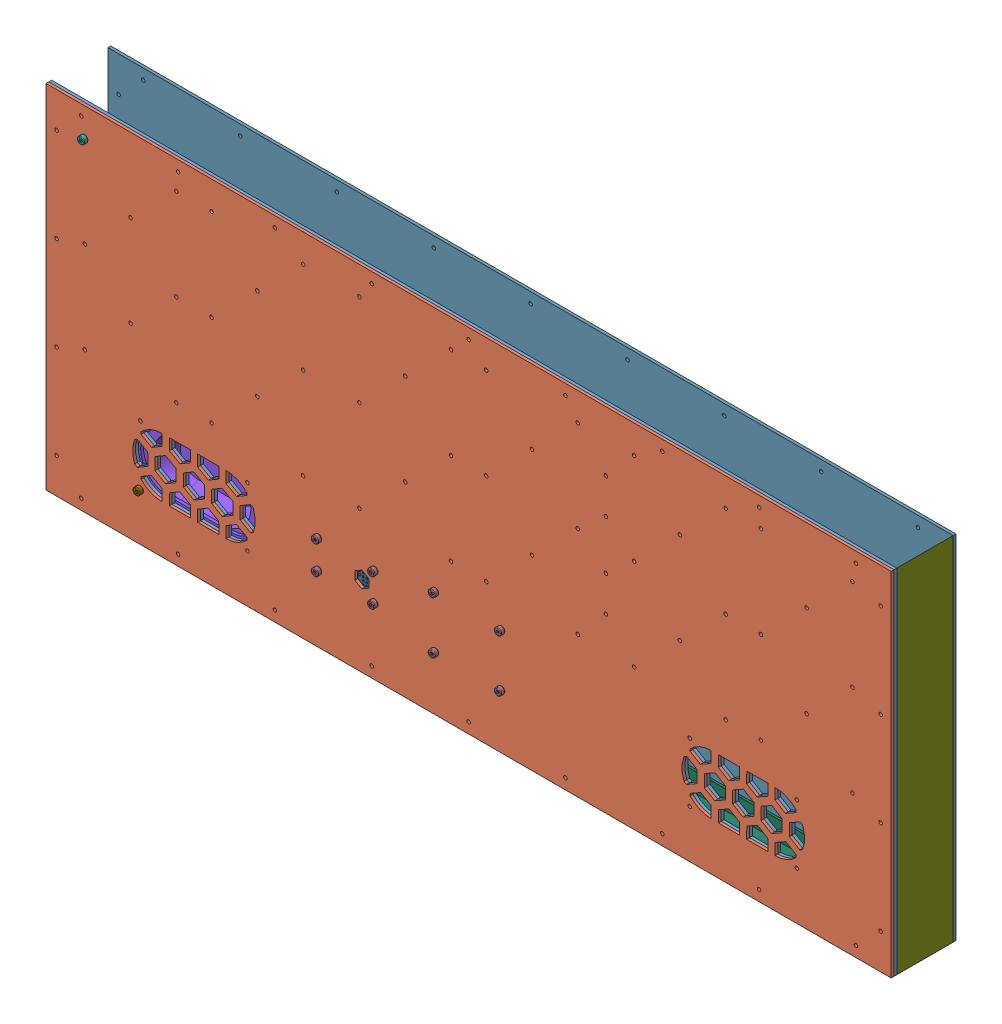
SolidWorks assembly Ensamblaje, configuration Predeterminado. Lengths in mm.
Overall size (600 250 31.87).
336 component instances, 16 part files, 54 mates.
Components (placement in the parent):
- Acrilico Frontal_back-1: Acrilico Frontal_back [Predeterminado] at (-375.8286 167.6436 436.4657) size (600 250 2)
- Acrilico Frontal_front-1: Acrilico Frontal_front [Predeterminado] at (-375.8286 167.6436 436.4657) size (600 250 2)
- Display-1: Display [Predeterminado] at (-610.5095 208.1102 290.9557) size (85 140 23) (hidden)
  - Display-1: Display [Predeterminado] at (-5.3191 -0.4666 134.5) size (85 140 11)
  - Ajuste Display-1: Ajuste Display [Predeterminado] at (-37.0959 64.7634 119.0956) size (6 6 23)
    - Separador-1: Separador [Predeterminado] at (-0.7232 -0.23 17.4044) size (6 6 9)
    - Tuerca M3-1: Tuerca M3 [Predeterminado] at (-0.7232 -0.23 13.4044) x (1 0 0) z (0 -1 0) size (5.77 2 5)
    - Tornillo M3x20_CC-1: Tornillo M3x20_CC [Predeterminado] at (-0.7232 -0.23 10.4144) size (5 5 23) (hidden)
  - Ajuste Display-2: Ajuste Display [Predeterminado] at (-4.5959 32.2634 119.0956) size (6 6 23)
    - Separador-1: Separador [Predeterminado] at (-0.7232 -0.23 17.4044) size (6 6 9)
    - Tuerca M3-1: Tuerca M3 [Predeterminado] at (-0.7232 -0.23 13.4044) x (1 0 0) z (0 -1 0) size (5.77 2 5)
    - Tornillo M3x20_CC-1: Tornillo M3x20_CC [Predeterminado] at (-0.7232 -0.23 10.4144) size (5 5 23) (hidden)
  - Ajuste Display-3: Ajuste Display [Predeterminado] at (-4.5959 -32.7366 119.0956) size (6 6 23)
    - Separador-1: Separador [Predeterminado] at (-0.7232 -0.23 17.4044) size (6 6 9)
    - Tuerca M3-1: Tuerca M3 [Predeterminado] at (-0.7232 -0.23 13.4044) x (1 0 0) z (0 -1 0) size (5.77 2 5)
    - Tornillo M3x20_CC-1: Tornillo M3x20_CC [Predeterminado] at (-0.7232 -0.23 10.4144) size (5 5 23) (hidden)
  - Ajuste Display-4: Ajuste Display [Predeterminado] at (-37.0959 -0.2366 119.0956) size (6 6 23)
    - Separador-1: Separador [Predeterminado] at (-0.7232 -0.23 17.4044) size (6 6 9)
    - Tuerca M3-1: Tuerca M3 [Predeterminado] at (-0.7232 -0.23 13.4044) x (1 0 0) z (0 -1 0) size (5.77 2 5)
    - Tornillo M3x20_CC-1: Tornillo M3x20_CC [Predeterminado] at (-0.7232 -0.23 10.4144) size (5 5 23) (hidden)
  - Ajuste Display-5: Ajuste Display [Predeterminado] at (-37.0959 -65.2366 119.0956) size (6 6 23)
    - Separador-1: Separador [Predeterminado] at (-0.7232 -0.23 17.4044) size (6 6 9)
    - Tuerca M3-1: Tuerca M3 [Predeterminado] at (-0.7232 -0.23 13.4044) x (1 0 0) z (0 -1 0) size (5.77 2 5)
    - Tornillo M3x20_CC-1: Tornillo M3x20_CC [Predeterminado] at (-0.7232 -0.23 10.4144) size (5 5 23) (hidden)
  - Ajuste Display-6: Ajuste Display [Predeterminado] at (27.9041 64.7634 119.0956) size (6 6 23)
    - Separador-1: Separador [Predeterminado] at (-0.7232 -0.23 17.4044) size (6 6 9)
    - Tuerca M3-1: Tuerca M3 [Predeterminado] at (-0.7232 -0.23 13.4044) x (1 0 0) z (0 -1 0) size (5.77 2 5)
    - Tornillo M3x20_CC-1: Tornillo M3x20_CC [Predeterminado] at (-0.7232 -0.23 10.4144) size (5 5 23) (hidden)
  - Ajuste Display-7: Ajuste Display [Predeterminado] at (27.9041 -0.2366 119.0956) size (6 6 23)
    - Separador-1: Separador [Predeterminado] at (-0.7232 -0.23 17.4044) size (6 6 9)
    - Tuerca M3-1: Tuerca M3 [Predeterminado] at (-0.7232 -0.23 13.4044) x (1 0 0) z (0 -1 0) size (5.77 2 5)
    - Tornillo M3x20_CC-1: Tornillo M3x20_CC [Predeterminado] at (-0.7232 -0.23 10.4144) size (5 5 23) (hidden)
  - Ajuste Display-8: Ajuste Display [Predeterminado] at (27.9041 -65.2366 119.0956) size (6 6 23)
    - Separador-1: Separador [Predeterminado] at (-0.7232 -0.23 17.4044) size (6 6 9)
    - Tuerca M3-1: Tuerca M3 [Predeterminado] at (-0.7232 -0.23 13.4044) x (1 0 0) z (0 -1 0) size (5.77 2 5)
    - Tornillo M3x20_CC-1: Tornillo M3x20_CC [Predeterminado] at (-0.7232 -0.23 10.4144) size (5 5 23) (hidden)
- Display-2: Display [Predeterminado] at (-130.5095 208.1102 290.9557) size (85 140 23) (hidden)
  - Display-1: Display [Predeterminado] at (-5.3191 -0.4666 134.5) size (85 140 11)
  - Ajuste Display-1: Ajuste Display [Predeterminado] at (-37.0959 64.7634 119.0956) size (6 6 23)
    - Separador-1: Separador [Predeterminado] at (-0.7232 -0.23 17.4044) size (6 6 9)
    - Tuerca M3-1: Tuerca M3 [Predeterminado] at (-0.7232 -0.23 13.4044) x (1 0 0) z (0 -1 0) size (5.77 2 5)
    - Tornillo M3x20_CC-1: Tornillo M3x20_CC [Predeterminado] at (-0.7232 -0.23 10.4144) size (5 5 23) (hidden)
  - Ajuste Display-2: Ajuste Display [Predeterminado] at (-4.5959 32.2634 119.0956) size (6 6 23)
    - Separador-1: Separador [Predeterminado] at (-0.7232 -0.23 17.4044) size (6 6 9)
    - Tuerca M3-1: Tuerca M3 [Predeterminado] at (-0.7232 -0.23 13.4044) x (1 0 0) z (0 -1 0) size (5.77 2 5)
    - Tornillo M3x20_CC-1: Tornillo M3x20_CC [Predeterminado] at (-0.7232 -0.23 10.4144) size (5 5 23) (hidden)
  - Ajuste Display-3: Ajuste Display [Predeterminado] at (-4.5959 -32.7366 119.0956) size (6 6 23)
    - Separador-1: Separador [Predeterminado] at (-0.7232 -0.23 17.4044) size (6 6 9)
    - Tuerca M3-1: Tuerca M3 [Predeterminado] at (-0.7232 -0.23 13.4044) x (1 0 0) z (0 -1 0) size (5.77 2 5)
    - Tornillo M3x20_CC-1: Tornillo M3x20_CC [Predeterminado] at (-0.7232 -0.23 10.4144) size (5 5 23) (hidden)
  - Ajuste Display-4: Ajuste Display [Predeterminado] at (-37.0959 -0.2366 119.0956) size (6 6 23)
    - Separador-1: Separador [Predeterminado] at (-0.7232 -0.23 17.4044) size (6 6 9)
    - Tuerca M3-1: Tuerca M3 [Predeterminado] at (-0.7232 -0.23 13.4044) x (1 0 0) z (0 -1 0) size (5.77 2 5)
    - Tornillo M3x20_CC-1: Tornillo M3x20_CC [Predeterminado] at (-0.7232 -0.23 10.4144) size (5 5 23) (hidden)
  - Ajuste Display-5: Ajuste Display [Predeterminado] at (-37.0959 -65.2366 119.0956) size (6 6 23)
    - Separador-1: Separador [Predeterminado] at (-0.7232 -0.23 17.4044) size (6 6 9)
    - Tuerca M3-1: Tuerca M3 [Predeterminado] at (-0.7232 -0.23 13.4044) x (1 0 0) z (0 -1 0) size (5.77 2 5)
    - Tornillo M3x20_CC-1: Tornillo M3x20_CC [Predeterminado] at (-0.7232 -0.23 10.4144) size (5 5 23) (hidden)
  - Ajuste Display-6: Ajuste Display [Predeterminado] at (27.9041 64.7634 119.0956) size (6 6 23)
    - Separador-1: Separador [Predeterminado] at (-0.7232 -0.23 17.4044) size (6 6 9)
    - Tuerca M3-1: Tuerca M3 [Predeterminado] at (-0.7232 -0.23 13.4044) x (1 0 0) z (0 -1 0) size (5.77 2 5)
    - Tornillo M3x20_CC-1: Tornillo M3x20_CC [Predeterminado] at (-0.7232 -0.23 10.4144) size (5 5 23) (hidden)
  - Ajuste Display-7: Ajuste Display [Predeterminado] at (27.9041 -0.2366 119.0956) size (6 6 23)
    - Separador-1: Separador [Predeterminado] at (-0.7232 -0.23 17.4044) size (6 6 9)
    - Tuerca M3-1: Tuerca M3 [Predeterminado] at (-0.7232 -0.23 13.4044) x (1 0 0) z (0 -1 0) size (5.77 2 5)
    - Tornillo M3x20_CC-1: Tornillo M3x20_CC [Predeterminado] at (-0.7232 -0.23 10.4144) size (5 5 23) (hidden)
  - Ajuste Display-8: Ajuste Display [Predeterminado] at (27.9041 -65.2366 119.0956) size (6 6 23)
    - Separador-1: Separador [Predeterminado] at (-0.7232 -0.23 17.4044) size (6 6 9)
    - Tuerca M3-1: Tuerca M3 [Predeterminado] at (-0.7232 -0.23 13.4044) x (1 0 0) z (0 -1 0) size (5.77 2 5)
    - Tornillo M3x20_CC-1: Tornillo M3x20_CC [Predeterminado] at (-0.7232 -0.23 10.4144) size (5 5 23) (hidden)
- Display-3: Display [Predeterminado] at (-220.5095 208.1102 290.9557) size (85 140 23) (hidden)
  - Display-1: Display [Predeterminado] at (-5.3191 -0.4666 134.5) size (85 140 11)
  - Ajuste Display-1: Ajuste Display [Predeterminado] at (-37.0959 64.7634 119.0956) size (6 6 23)
    - Separador-1: Separador [Predeterminado] at (-0.7232 -0.23 17.4044) size (6 6 9)
    - Tuerca M3-1: Tuerca M3 [Predeterminado] at (-0.7232 -0.23 13.4044) x (1 0 0) z (0 -1 0) size (5.77 2 5)
    - Tornillo M3x20_CC-1: Tornillo M3x20_CC [Predeterminado] at (-0.7232 -0.23 10.4144) size (5 5 23) (hidden)
  - Ajuste Display-2: Ajuste Display [Predeterminado] at (-4.5959 32.2634 119.0956) size (6 6 23)
    - Separador-1: Separador [Predeterminado] at (-0.7232 -0.23 17.4044) size (6 6 9)
    - Tuerca M3-1: Tuerca M3 [Predeterminado] at (-0.7232 -0.23 13.4044) x (1 0 0) z (0 -1 0) size (5.77 2 5)
    - Tornillo M3x20_CC-1: Tornillo M3x20_CC [Predeterminado] at (-0.7232 -0.23 10.4144) size (5 5 23) (hidden)
  - Ajuste Display-3: Ajuste Display [Predeterminado] at (-4.5959 -32.7366 119.0956) size (6 6 23)
    - Separador-1: Separador [Predeterminado] at (-0.7232 -0.23 17.4044) size (6 6 9)
    - Tuerca M3-1: Tuerca M3 [Predeterminado] at (-0.7232 -0.23 13.4044) x (1 0 0) z (0 -1 0) size (5.77 2 5)
    - Tornillo M3x20_CC-1: Tornillo M3x20_CC [Predeterminado] at (-0.7232 -0.23 10.4144) size (5 5 23) (hidden)
  - Ajuste Display-4: Ajuste Display [Predeterminado] at (-37.0959 -0.2366 119.0956) size (6 6 23)
    - Separador-1: Separador [Predeterminado] at (-0.7232 -0.23 17.4044) size (6 6 9)
    - Tuerca M3-1: Tuerca M3 [Predeterminado] at (-0.7232 -0.23 13.4044) x (1 0 0) z (0 -1 0) size (5.77 2 5)
    - Tornillo M3x20_CC-1: Tornillo M3x20_CC [Predeterminado] at (-0.7232 -0.23 10.4144) size (5 5 23) (hidden)
  - Ajuste Display-5: Ajuste Display [Predeterminado] at (-37.0959 -65.2366 119.0956) size (6 6 23)
    - Separador-1: Separador [Predeterminado] at (-0.7232 -0.23 17.4044) size (6 6 9)
    - Tuerca M3-1: Tuerca M3 [Predeterminado] at (-0.7232 -0.23 13.4044) x (1 0 0) z (0 -1 0) size (5.77 2 5)
    - Tornillo M3x20_CC-1: Tornillo M3x20_CC [Predeterminado] at (-0.7232 -0.23 10.4144) size (5 5 23) (hidden)
  - Ajuste Display-6: Ajuste Display [Predeterminado] at (27.9041 64.7634 119.0956) size (6 6 23)
    - Separador-1: Separador [Predeterminado] at (-0.7232 -0.23 17.4044) size (6 6 9)
    - Tuerca M3-1: Tuerca M3 [Predeterminado] at (-0.7232 -0.23 13.4044) x (1 0 0) z (0 -1 0) size (5.77 2 5)
    - Tornillo M3x20_CC-1: Tornillo M3x20_CC [Predeterminado] at (-0.7232 -0.23 10.4144) size (5 5 23) (hidden)
  - Ajuste Display-7: Ajuste Display [Predeterminado] at (27.9041 -0.2366 119.0956) size (6 6 23)
    - Separador-1: Separador [Predeterminado] at (-0.7232 -0.23 17.4044) size (6 6 9)
    - Tuerca M3-1: Tuerca M3 [Predeterminado] at (-0.7232 -0.23 13.4044) x (1 0 0) z (0 -1 0) size (5.77 2 5)
    - Tornillo M3x20_CC-1: Tornillo M3x20_CC [Predeterminado] at (-0.7232 -0.23 10.4144) size (5 5 23) (hidden)
  - Ajuste Display-8: Ajuste Display [Predeterminado] at (27.9041 -65.2366 119.0956) size (6 6 23)
    - Separador-1: Separador [Predeterminado] at (-0.7232 -0.23 17.4044) size (6 6 9)
    - Tuerca M3-1: Tuerca M3 [Predeterminado] at (-0.7232 -0.23 13.4044) x (1 0 0) z (0 -1 0) size (5.77 2 5)
    - Tornillo M3x20_CC-1: Tornillo M3x20_CC [Predeterminado] at (-0.7232 -0.23 10.4144) size (5 5 23) (hidden)
- Display-4: Display [Predeterminado] at (-325.5095 208.1102 290.9557) size (85 140 23) (hidden)
  - Display-1: Display [Predeterminado] at (-5.3191 -0.4666 134.5) size (85 140 11)
  - Ajuste Display-1: Ajuste Display [Predeterminado] at (-37.0959 64.7634 119.0956) size (6 6 23)
    - Separador-1: Separador [Predeterminado] at (-0.7232 -0.23 17.4044) size (6 6 9)
    - Tuerca M3-1: Tuerca M3 [Predeterminado] at (-0.7232 -0.23 13.4044) x (1 0 0) z (0 -1 0) size (5.77 2 5)
    - Tornillo M3x20_CC-1: Tornillo M3x20_CC [Predeterminado] at (-0.7232 -0.23 10.4144) size (5 5 23) (hidden)
  - Ajuste Display-2: Ajuste Display [Predeterminado] at (-4.5959 32.2634 119.0956) size (6 6 23)
    - Separador-1: Separador [Predeterminado] at (-0.7232 -0.23 17.4044) size (6 6 9)
    - Tuerca M3-1: Tuerca M3 [Predeterminado] at (-0.7232 -0.23 13.4044) x (1 0 0) z (0 -1 0) size (5.77 2 5)
    - Tornillo M3x20_CC-1: Tornillo M3x20_CC [Predeterminado] at (-0.7232 -0.23 10.4144) size (5 5 23) (hidden)
  - Ajuste Display-3: Ajuste Display [Predeterminado] at (-4.5959 -32.7366 119.0956) size (6 6 23)
    - Separador-1: Separador [Predeterminado] at (-0.7232 -0.23 17.4044) size (6 6 9)
    - Tuerca M3-1: Tuerca M3 [Predeterminado] at (-0.7232 -0.23 13.4044) x (1 0 0) z (0 -1 0) size (5.77 2 5)
    - Tornillo M3x20_CC-1: Tornillo M3x20_CC [Predeterminado] at (-0.7232 -0.23 10.4144) size (5 5 23) (hidden)
  - Ajuste Display-4: Ajuste Display [Predeterminado] at (-37.0959 -0.2366 119.0956) size (6 6 23)
    - Separador-1: Separador [Predeterminado] at (-0.7232 -0.23 17.4044) size (6 6 9)
    - Tuerca M3-1: Tuerca M3 [Predeterminado] at (-0.7232 -0.23 13.4044) x (1 0 0) z (0 -1 0) size (5.77 2 5)
    - Tornillo M3x20_CC-1: Tornillo M3x20_CC [Predeterminado] at (-0.7232 -0.23 10.4144) size (5 5 23) (hidden)
  - Ajuste Display-5: Ajuste Display [Predeterminado] at (-37.0959 -65.2366 119.0956) size (6 6 23)
    - Separador-1: Separador [Predeterminado] at (-0.7232 -0.23 17.4044) size (6 6 9)
    - Tuerca M3-1: Tuerca M3 [Predeterminado] at (-0.7232 -0.23 13.4044) x (1 0 0) z (0 -1 0) size (5.77 2 5)
    - Tornillo M3x20_CC-1: Tornillo M3x20_CC [Predeterminado] at (-0.7232 -0.23 10.4144) size (5 5 23) (hidden)
  - Ajuste Display-6: Ajuste Display [Predeterminado] at (27.9041 64.7634 119.0956) size (6 6 23)
    - Separador-1: Separador [Predeterminado] at (-0.7232 -0.23 17.4044) size (6 6 9)
    - Tuerca M3-1: Tuerca M3 [Predeterminado] at (-0.7232 -0.23 13.4044) x (1 0 0) z (0 -1 0) size (5.77 2 5)
    - Tornillo M3x20_CC-1: Tornillo M3x20_CC [Predeterminado] at (-0.7232 -0.23 10.4144) size (5 5 23) (hidden)
  - Ajuste Display-7: Ajuste Display [Predeterminado] at (27.9041 -0.2366 119.0956) size (6 6 23)
    - Separador-1: Separador [Predeterminado] at (-0.7232 -0.23 17.4044) size (6 6 9)
    - Tuerca M3-1: Tuerca M3 [Predeterminado] at (-0.7232 -0.23 13.4044) x (1 0 0) z (0 -1 0) size (5.77 2 5)
    - Tornillo M3x20_CC-1: Tornillo M3x20_CC [Predeterminado] at (-0.7232 -0.23 10.4144) size (5 5 23) (hidden)
  - Ajuste Display-8: Ajuste Display [Predeterminado] at (27.9041 -65.2366 119.0956) size (6 6 23)
    - Separador-1: Separador [Predeterminado] at (-0.7232 -0.23 17.4044) size (6 6 9)
    - Tuerca M3-1: Tuerca M3 [Predeterminado] at (-0.7232 -0.23 13.4044) x (1 0 0) z (0 -1 0) size (5.77 2 5)
    - Tornillo M3x20_CC-1: Tornillo M3x20_CC [Predeterminado] at (-0.7232 -0.23 10.4144) size (5 5 23) (hidden)
- Display-5: Display [Predeterminado] at (-415.5095 208.1102 290.9557) size (85 140 23) (hidden)
  - Display-1: Display [Predeterminado] at (-5.3191 -0.4666 134.5) size (85 140 11)
  - Ajuste Display-1: Ajuste Display [Predeterminado] at (-37.0959 64.7634 119.0956) size (6 6 23)
    - Separador-1: Separador [Predeterminado] at (-0.7232 -0.23 17.4044) size (6 6 9)
    - Tuerca M3-1: Tuerca M3 [Predeterminado] at (-0.7232 -0.23 13.4044) x (1 0 0) z (0 -1 0) size (5.77 2 5)
    - Tornillo M3x20_CC-1: Tornillo M3x20_CC [Predeterminado] at (-0.7232 -0.23 10.4144) size (5 5 23) (hidden)
  - Ajuste Display-2: Ajuste Display [Predeterminado] at (-4.5959 32.2634 119.0956) size (6 6 23)
    - Separador-1: Separador [Predeterminado] at (-0.7232 -0.23 17.4044) size (6 6 9)
    - Tuerca M3-1: Tuerca M3 [Predeterminado] at (-0.7232 -0.23 13.4044) x (1 0 0) z (0 -1 0) size (5.77 2 5)
    - Tornillo M3x20_CC-1: Tornillo M3x20_CC [Predeterminado] at (-0.7232 -0.23 10.4144) size (5 5 23) (hidden)
  - Ajuste Display-3: Ajuste Display [Predeterminado] at (-4.5959 -32.7366 119.0956) size (6 6 23)
    - Separador-1: Separador [Predeterminado] at (-0.7232 -0.23 17.4044) size (6 6 9)
    - Tuerca M3-1: Tuerca M3 [Predeterminado] at (-0.7232 -0.23 13.4044) x (1 0 0) z (0 -1 0) size (5.77 2 5)
    - Tornillo M3x20_CC-1: Tornillo M3x20_CC [Predeterminado] at (-0.7232 -0.23 10.4144) size (5 5 23) (hidden)
  - Ajuste Display-4: Ajuste Display [Predeterminado] at (-37.0959 -0.2366 119.0956) size (6 6 23)
    - Separador-1: Separador [Predeterminado] at (-0.7232 -0.23 17.4044) size (6 6 9)
    - Tuerca M3-1: Tuerca M3 [Predeterminado] at (-0.7232 -0.23 13.4044) x (1 0 0) z (0 -1 0) size (5.77 2 5)
    - Tornillo M3x20_CC-1: Tornillo M3x20_CC [Predeterminado] at (-0.7232 -0.23 10.4144) size (5 5 23) (hidden)
  - Ajuste Display-5: Ajuste Display [Predeterminado] at (-37.0959 -65.2366 119.0956) size (6 6 23)
    - Separador-1: Separador [Predeterminado] at (-0.7232 -0.23 17.4044) size (6 6 9)
    - Tuerca M3-1: Tuerca M3 [Predeterminado] at (-0.7232 -0.23 13.4044) x (1 0 0) z (0 -1 0) size (5.77 2 5)
    - Tornillo M3x20_CC-1: Tornillo M3x20_CC [Predeterminado] at (-0.7232 -0.23 10.4144) size (5 5 23) (hidden)
  - Ajuste Display-6: Ajuste Display [Predeterminado] at (27.9041 64.7634 119.0956) size (6 6 23)
    - Separador-1: Separador [Predeterminado] at (-0.7232 -0.23 17.4044) size (6 6 9)
    - Tuerca M3-1: Tuerca M3 [Predeterminado] at (-0.7232 -0.23 13.4044) x (1 0 0) z (0 -1 0) size (5.77 2 5)
    - Tornillo M3x20_CC-1: Tornillo M3x20_CC [Predeterminado] at (-0.7232 -0.23 10.4144) size (5 5 23) (hidden)
  - Ajuste Display-7: Ajuste Display [Predeterminado] at (27.9041 -0.2366 119.0956) size (6 6 23)
    - Separador-1: Separador [Predeterminado] at (-0.7232 -0.23 17.4044) size (6 6 9)
    - Tuerca M3-1: Tuerca M3 [Predeterminado] at (-0.7232 -0.23 13.4044) x (1 0 0) z (0 -1 0) size (5.77 2 5)
    - Tornillo M3x20_CC-1: Tornillo M3x20_CC [Predeterminado] at (-0.7232 -0.23 10.4144) size (5 5 23) (hidden)
  - Ajuste Display-8: Ajuste Display [Predeterminado] at (27.9041 -65.2366 119.0956) size (6 6 23)
    - Separador-1: Separador [Predeterminado] at (-0.7232 -0.23 17.4044) size (6 6 9)
    - Tuerca M3-1: Tuerca M3 [Predeterminado] at (-0.7232 -0.23 13.4044) x (1 0 0) z (0 -1 0) size (5.77 2 5)
    - Tornillo M3x20_CC-1: Tornillo M3x20_CC [Predeterminado] at (-0.7232 -0.23 10.4144) size (5 5 23) (hidden)
- Display-6: Display [Predeterminado] at (-520.5095 208.1102 290.9557) size (85 140 23) (hidden)
  - Display-1: Display [Predeterminado] at (-5.3191 -0.4666 134.5) size (85 140 11)
  - Ajuste Display-1: Ajuste Display [Predeterminado] at (-37.0959 64.7634 119.0956) size (6 6 23)
    - Separador-1: Separador [Predeterminado] at (-0.7232 -0.23 17.4044) size (6 6 9)
    - Tuerca M3-1: Tuerca M3 [Predeterminado] at (-0.7232 -0.23 13.4044) x (1 0 0) z (0 -1 0) size (5.77 2 5)
    - Tornillo M3x20_CC-1: Tornillo M3x20_CC [Predeterminado] at (-0.7232 -0.23 10.4144) size (5 5 23) (hidden)
  - Ajuste Display-2: Ajuste Display [Predeterminado] at (-4.5959 32.2634 119.0956) size (6 6 23)
    - Separador-1: Separador [Predeterminado] at (-0.7232 -0.23 17.4044) size (6 6 9)
    - Tuerca M3-1: Tuerca M3 [Predeterminado] at (-0.7232 -0.23 13.4044) x (1 0 0) z (0 -1 0) size (5.77 2 5)
    - Tornillo M3x20_CC-1: Tornillo M3x20_CC [Predeterminado] at (-0.7232 -0.23 10.4144) size (5 5 23) (hidden)
  - Ajuste Display-3: Ajuste Display [Predeterminado] at (-4.5959 -32.7366 119.0956) size (6 6 23)
    - Separador-1: Separador [Predeterminado] at (-0.7232 -0.23 17.4044) size (6 6 9)
    - Tuerca M3-1: Tuerca M3 [Predeterminado] at (-0.7232 -0.23 13.4044) x (1 0 0) z (0 -1 0) size (5.77 2 5)
    - Tornillo M3x20_CC-1: Tornillo M3x20_CC [Predeterminado] at (-0.7232 -0.23 10.4144) size (5 5 23) (hidden)
  - Ajuste Display-4: Ajuste Display [Predeterminado] at (-37.0959 -0.2366 119.0956) size (6 6 23)
    - Separador-1: Separador [Predeterminado] at (-0.7232 -0.23 17.4044) size (6 6 9)
    - Tuerca M3-1: Tuerca M3 [Predeterminado] at (-0.7232 -0.23 13.4044) x (1 0 0) z (0 -1 0) size (5.77 2 5)
    - Tornillo M3x20_CC-1: Tornillo M3x20_CC [Predeterminado] at (-0.7232 -0.23 10.4144) size (5 5 23) (hidden)
  - Ajuste Display-5: Ajuste Display [Predeterminado] at (-37.0959 -65.2366 119.0956) size (6 6 23)
    - Separador-1: Separador [Predeterminado] at (-0.7232 -0.23 17.4044) size (6 6 9)
    - Tuerca M3-1: Tuerca M3 [Predeterminado] at (-0.7232 -0.23 13.4044) x (1 0 0) z (0 -1 0) size (5.77 2 5)
    - Tornillo M3x20_CC-1: Tornillo M3x20_CC [Predeterminado] at (-0.7232 -0.23 10.4144) size (5 5 23) (hidden)
  - Ajuste Display-6: Ajuste Display [Predeterminado] at (27.9041 64.7634 119.0956) size (6 6 23)
    - Separador-1: Separador [Predeterminado] at (-0.7232 -0.23 17.4044) size (6 6 9)
    - Tuerca M3-1: Tuerca M3 [Predeterminado] at (-0.7232 -0.23 13.4044) x (1 0 0) z (0 -1 0) size (5.77 2 5)
    - Tornillo M3x20_CC-1: Tornillo M3x20_CC [Predeterminado] at (-0.7232 -0.23 10.4144) size (5 5 23) (hidden)
  - Ajuste Display-7: Ajuste Display [Predeterminado] at (27.9041 -0.2366 119.0956) size (6 6 23)
    - Separador-1: Separador [Predeterminado] at (-0.7232 -0.23 17.4044) size (6 6 9)
    - Tuerca M3-1: Tuerca M3 [Predeterminado] at (-0.7232 -0.23 13.4044) x (1 0 0) z (0 -1 0) size (5.77 2 5)
    - Tornillo M3x20_CC-1: Tornillo M3x20_CC [Predeterminado] at (-0.7232 -0.23 10.4144) size (5 5 23) (hidden)
  - Ajuste Display-8: Ajuste Display [Predeterminado] at (27.9041 -65.2366 119.0956) size (6 6 23)
    - Separador-1: Separador [Predeterminado] at (-0.7232 -0.23 17.4044) size (6 6 9)
    - Tuerca M3-1: Tuerca M3 [Predeterminado] at (-0.7232 -0.23 13.4044) x (1 0 0) z (0 -1 0) size (5.77 2 5)
    - Tornillo M3x20_CC-1: Tornillo M3x20_CC [Predeterminado] at (-0.7232 -0.23 10.4144) size (5 5 23) (hidden)
- Dospuntos-1: Dospuntos [Predeterminado] at (-260.2649 210.5098 330.9557) size (15 100 23) (hidden)
  - PlacaDospuntos-1: PlacaDospuntos [Predeterminado] at (-18.0638 -2.8662 96.5) size (15 100 11)
  - Ajuste Display-1: Ajuste Display [Predeterminado] at (-17.3405 39.8638 79.0956) size (6 6 23)
    - Separador-1: Separador [Predeterminado] at (-0.7232 -0.23 17.4044) size (6 6 9)
    - Tuerca M3-1: Tuerca M3 [Predeterminado] at (-0.7232 -0.23 13.4044) x (1 0 0) z (0 -1 0) size (5.77 2 5)
    - Tornillo M3x20_CC-1: Tornillo M3x20_CC [Predeterminado] at (-0.7232 -0.23 10.4144) size (5 5 23) (hidden)
  - Ajuste Display-2: Ajuste Display [Predeterminado] at (-17.3405 14.8638 79.0956) size (6 6 23)
    - Separador-1: Separador [Predeterminado] at (-0.7232 -0.23 17.4044) size (6 6 9)
    - Tuerca M3-1: Tuerca M3 [Predeterminado] at (-0.7232 -0.23 13.4044) x (1 0 0) z (0 -1 0) size (5.77 2 5)
    - Tornillo M3x20_CC-1: Tornillo M3x20_CC [Predeterminado] at (-0.7232 -0.23 10.4144) size (5 5 23) (hidden)
  - Ajuste Display-3: Ajuste Display [Predeterminado] at (-17.3405 -20.1362 79.0956) size (6 6 23)
    - Separador-1: Separador [Predeterminado] at (-0.7232 -0.23 17.4044) size (6 6 9)
    - Tuerca M3-1: Tuerca M3 [Predeterminado] at (-0.7232 -0.23 13.4044) x (1 0 0) z (0 -1 0) size (5.77 2 5)
    - Tornillo M3x20_CC-1: Tornillo M3x20_CC [Predeterminado] at (-0.7232 -0.23 10.4144) size (5 5 23) (hidden)
  - Ajuste Display-4: Ajuste Display [Predeterminado] at (-17.3405 -45.1362 79.0956) size (6 6 23)
    - Separador-1: Separador [Predeterminado] at (-0.7232 -0.23 17.4044) size (6 6 9)
    - Tuerca M3-1: Tuerca M3 [Predeterminado] at (-0.7232 -0.23 13.4044) x (1 0 0) z (0 -1 0) size (5.77 2 5)
    - Tornillo M3x20_CC-1: Tornillo M3x20_CC [Predeterminado] at (-0.7232 -0.23 10.4144) size (5 5 23) (hidden)
- Parl-1: Parl [Predeterminado] at (-575.2079 114.8609 334.9557) x (0 1 0) z (0 0 1) size (50 90 30.01) (hidden)
  - Parlante-1: Parlante [Predeterminado] at (-17.2172 -4.3793 98.5) size (50 90 23)
  - Tornillo M3x10_CC-1: Tornillo M3x10_CC [Predeterminado] at (-38.2172 33.6207 95.51) size (5 5 13)
  - Tornillo M3x10_CC-2: Tornillo M3x10_CC [Predeterminado] at (3.7828 33.6207 95.51) size (5 5 13)
  - Tornillo M3x10_CC-3: Tornillo M3x10_CC [Predeterminado] at (-38.2172 -42.3793 95.51) size (5 5 13)
  - Tornillo M3x10_CC-4: Tornillo M3x10_CC [Predeterminado] at (3.7828 -42.3793 95.51) size (5 5 13)
  - Tuerca M3-1: Tuerca M3 [Predeterminado] at (-38.2172 33.6207 96.5) x (1 0 0) z (0 -1 0) size (5.77 2 5)
  - Tuerca M3-2: Tuerca M3 [Predeterminado] at (3.7828 33.6207 96.5) x (1 0 0) z (0 -1 0) size (5.77 2 5)
  - Tuerca M3-3: Tuerca M3 [Predeterminado] at (3.7828 -42.3793 96.5) x (1 0 0) z (0 -1 0) size (5.77 2 5)
  - Tuerca M3-4: Tuerca M3 [Predeterminado] at (-38.2172 -42.3793 96.5) x (1 0 0) z (0 -1 0) size (5.77 2 5)
- Parl-2: Parl [Predeterminado] at (-185.2079 114.8609 334.9557) x (0 1 0) z (0 0 1) size (50 90 30.01) (hidden)
  - Parlante-1: Parlante [Predeterminado] at (-17.2172 -4.3793 98.5) size (50 90 23)
  - Tornillo M3x10_CC-1: Tornillo M3x10_CC [Predeterminado] at (-38.2172 33.6207 95.51) size (5 5 13)
  - Tornillo M3x10_CC-2: Tornillo M3x10_CC [Predeterminado] at (3.7828 33.6207 95.51) size (5 5 13)
  - Tornillo M3x10_CC-3: Tornillo M3x10_CC [Predeterminado] at (-38.2172 -42.3793 95.51) size (5 5 13)
  - Tornillo M3x10_CC-4: Tornillo M3x10_CC [Predeterminado] at (3.7828 -42.3793 95.51) size (5 5 13)
  - Tuerca M3-1: Tuerca M3 [Predeterminado] at (-38.2172 33.6207 96.5) x (1 0 0) z (0 -1 0) size (5.77 2 5)
  - Tuerca M3-2: Tuerca M3 [Predeterminado] at (3.7828 33.6207 96.5) x (1 0 0) z (0 -1 0) size (5.77 2 5)
  - Tuerca M3-3: Tuerca M3 [Predeterminado] at (3.7828 -42.3793 96.5) x (1 0 0) z (0 -1 0) size (5.77 2 5)
  - Tuerca M3-4: Tuerca M3 [Predeterminado] at (-38.2172 -42.3793 96.5) x (1 0 0) z (0 -1 0) size (5.77 2 5)
- dht+ir-1: dht+ir [Predeterminado] at (-470.8286 100.6436 430.8407) x (0 1 0) z (0 0 1) size (26 48 10.3)
- Mainboard-1: Mainboard [Predeterminado] at (-373.3286 100.1436 430.8407) x (0 -1 0) z (0 0 -1) size (45 55 28.62)
- Ajuste Placas-1: Ajuste Placas [Predeterminado] at (-441.912 110.1936 411.0674) size (6 6 18)
  - Separador 5mm-1: Separador 5mm [Predeterminado] at (-0.4166 -0.05 20.3883) size (6 6 5)
  - Tuerca M3-1: Tuerca M3 [Predeterminado] at (-0.4166 -0.05 16.3983) x (1 0 0) z (0 -1 0) size (5.77 2 5)
  - Tornillo M3x15_CC-1: Tornillo M3x15_CC [Predeterminado] at (-0.4166 -0.05 14.3983) size (5 5 18)
- Ajuste Placas-2: Ajuste Placas [Predeterminado] at (-481.912 90.1936 411.0674) size (6 6 18)
  - Separador 5mm-1: Separador 5mm [Predeterminado] at (-0.4166 -0.05 20.3883) size (6 6 5)
  - Tuerca M3-1: Tuerca M3 [Predeterminado] at (-0.4166 -0.05 16.3983) x (1 0 0) z (0 -1 0) size (5.77 2 5)
  - Tornillo M3x15_CC-1: Tornillo M3x15_CC [Predeterminado] at (-0.4166 -0.05 14.3983) size (5 5 18)
- Ajuste Placas-3: Ajuste Placas [Predeterminado] at (-481.912 110.1936 411.0674) size (6 6 18)
  - Separador 5mm-1: Separador 5mm [Predeterminado] at (-0.4166 -0.05 20.3883) size (6 6 5)
  - Tuerca M3-1: Tuerca M3 [Predeterminado] at (-0.4166 -0.05 16.3983) x (1 0 0) z (0 -1 0) size (5.77 2 5)
  - Tornillo M3x15_CC-1: Tornillo M3x15_CC [Predeterminado] at (-0.4166 -0.05 14.3983) size (5 5 18)
- Ajuste Placas-4: Ajuste Placas [Predeterminado] at (-441.912 90.1936 411.0674) size (6 6 18)
  - Separador 5mm-1: Separador 5mm [Predeterminado] at (-0.4166 -0.05 20.3883) size (6 6 5)
  - Tuerca M3-1: Tuerca M3 [Predeterminado] at (-0.4166 -0.05 16.3983) x (1 0 0) z (0 -1 0) size (5.77 2 5)
  - Tornillo M3x15_CC-1: Tornillo M3x15_CC [Predeterminado] at (-0.4166 -0.05 14.3983) size (5 5 18)
- Ajuste Placas-5: Ajuste Placas [Predeterminado] at (-398.912 81.6936 411.0674) size (6 6 18)
  - Separador 5mm-1: Separador 5mm [Predeterminado] at (-0.4166 -0.05 20.3883) size (6 6 5)
  - Tuerca M3-1: Tuerca M3 [Predeterminado] at (-0.4166 -0.05 16.3983) x (1 0 0) z (0 -1 0) size (5.77 2 5)
  - Tornillo M3x15_CC-1: Tornillo M3x15_CC [Predeterminado] at (-0.4166 -0.05 14.3983) size (5 5 18)
- Ajuste Placas-6: Ajuste Placas [Predeterminado] at (-351.912 118.6936 411.0674) size (6 6 18)
  - Separador 5mm-1: Separador 5mm [Predeterminado] at (-0.4166 -0.05 20.3883) size (6 6 5)
  - Tuerca M3-1: Tuerca M3 [Predeterminado] at (-0.4166 -0.05 16.3983) x (1 0 0) z (0 -1 0) size (5.77 2 5)
  - Tornillo M3x15_CC-1: Tornillo M3x15_CC [Predeterminado] at (-0.4166 -0.05 14.3983) size (5 5 18)
- Ajuste Placas-7: Ajuste Placas [Predeterminado] at (-398.912 118.6936 411.0674) size (6 6 18)
  - Separador 5mm-1: Separador 5mm [Predeterminado] at (-0.4166 -0.05 20.3883) size (6 6 5)
  - Tuerca M3-1: Tuerca M3 [Predeterminado] at (-0.4166 -0.05 16.3983) x (1 0 0) z (0 -1 0) size (5.77 2 5)
  - Tornillo M3x15_CC-1: Tornillo M3x15_CC [Predeterminado] at (-0.4166 -0.05 14.3983) size (5 5 18)
- Ajuste Placas-8: Ajuste Placas [Predeterminado] at (-351.912 81.6936 411.0674) size (6 6 18)
  - Separador 5mm-1: Separador 5mm [Predeterminado] at (-0.4166 -0.05 20.3883) size (6 6 5)
  - Tuerca M3-1: Tuerca M3 [Predeterminado] at (-0.4166 -0.05 16.3983) x (1 0 0) z (0 -1 0) size (5.77 2 5)
  - Tornillo M3x15_CC-1: Tornillo M3x15_CC [Predeterminado] at (-0.4166 -0.05 14.3983) size (5 5 18)
- Acrilico Trasero-1: Acrilico Trasero [Predeterminado] at (-375.8286 167.6436 394.4457) size (600 250 2) (hidden)
- Perfiles-1: Perfiles [Predeterminado] at (-264.7102 -96.0212 -97.1444) size (600 250 52.02) (hidden)
  - Tornillo M3x10_CC-1: Tornillo M3x10_CC [Predeterminado] at (-386.1185 381.1648 527.6101) size (5 5 13)
  - Tornillo M3x10_CC-2: Tornillo M3x10_CC [Predeterminado] at (-403.6185 363.6648 527.6101) size (5 5 13)
  - Tornillo M3x10_CC-3: Tornillo M3x10_CC [Predeterminado] at (-403.6185 363.6648 501.5901) x (1 0 0) z (0 0 -1) size (5 5 13)
  - Tornillo M3x10_CC-4: Tornillo M3x10_CC [Predeterminado] at (-386.1185 381.1648 501.5901) x (1 0 0) z (0 0 -1) size (5 5 13)
  - Tornillo M3x10_CC-5: Tornillo M3x10_CC [Predeterminado] at (-386.1185 146.1648 501.5901) x (1 0 0) z (0 0 -1) size (5 5 13)
  - Tornillo M3x10_CC-6: Tornillo M3x10_CC [Predeterminado] at (-317.3685 381.1648 501.5901) x (1 0 0) z (0 0 -1) size (5 5 13)
  - Tornillo M3x10_CC-7: Tornillo M3x10_CC [Predeterminado] at (-317.3685 146.1648 501.5901) x (1 0 0) z (0 0 -1) size (5 5 13)
  - Tornillo M3x10_CC-8: Tornillo M3x10_CC [Predeterminado] at (-248.6185 381.1648 501.5901) x (1 0 0) z (0 0 -1) size (5 5 13)
  - Tornillo M3x10_CC-9: Tornillo M3x10_CC [Predeterminado] at (-248.6185 146.1648 501.5901) x (1 0 0) z (0 0 -1) size (5 5 13)
  - Tornillo M3x10_CC-10: Tornillo M3x10_CC [Predeterminado] at (-179.8685 381.1648 501.5901) x (1 0 0) z (0 0 -1) size (5 5 13)
  - Tornillo M3x10_CC-11: Tornillo M3x10_CC [Predeterminado] at (-179.8685 146.1648 501.5901) x (1 0 0) z (0 0 -1) size (5 5 13)
  - Tornillo M3x10_CC-12: Tornillo M3x10_CC [Predeterminado] at (-111.1185 381.1648 501.5901) x (1 0 0) z (0 0 -1) size (5 5 13)
  - Tornillo M3x10_CC-13: Tornillo M3x10_CC [Predeterminado] at (-111.1185 146.1648 501.5901) x (1 0 0) z (0 0 -1) size (5 5 13)
  - Tornillo M3x10_CC-14: Tornillo M3x10_CC [Predeterminado] at (-42.3685 381.1648 501.5901) x (1 0 0) z (0 0 -1) size (5 5 13)
  - Tornillo M3x10_CC-15: Tornillo M3x10_CC [Predeterminado] at (-42.3685 146.1648 501.5901) x (1 0 0) z (0 0 -1) size (5 5 13)
  - Tornillo M3x10_CC-16: Tornillo M3x10_CC [Predeterminado] at (26.3815 381.1648 501.5901) x (1 0 0) z (0 0 -1) size (5 5 13)
  - Tornillo M3x10_CC-17: Tornillo M3x10_CC [Predeterminado] at (26.3815 146.1648 501.5901) x (1 0 0) z (0 0 -1) size (5 5 13)
  - Tornillo M3x10_CC-18: Tornillo M3x10_CC [Predeterminado] at (95.1315 381.1648 501.5901) x (1 0 0) z (0 0 -1) size (5 5 13)
  - Tornillo M3x10_CC-19: Tornillo M3x10_CC [Predeterminado] at (95.1315 146.1648 501.5901) x (1 0 0) z (0 0 -1) size (5 5 13)
  - Tornillo M3x10_CC-20: Tornillo M3x10_CC [Predeterminado] at (163.8815 381.1648 501.5901) x (1 0 0) z (0 0 -1) size (5 5 13)
  - Tornillo M3x10_CC-21: Tornillo M3x10_CC [Predeterminado] at (163.8815 146.1648 501.5901) x (1 0 0) z (0 0 -1) size (5 5 13)
  - Tornillo M3x10_CC-22: Tornillo M3x10_CC [Predeterminado] at (-386.1185 146.1648 527.6101) size (5 5 13)
  - Tornillo M3x10_CC-23: Tornillo M3x10_CC [Predeterminado] at (-317.3685 381.1648 527.6101) size (5 5 13)
  - Tornillo M3x10_CC-24: Tornillo M3x10_CC [Predeterminado] at (-317.3685 146.1648 527.6101) size (5 5 13)
  - Tornillo M3x10_CC-25: Tornillo M3x10_CC [Predeterminado] at (-248.6185 381.1648 527.6101) size (5 5 13)
  - Tornillo M3x10_CC-26: Tornillo M3x10_CC [Predeterminado] at (-248.6185 146.1648 527.6101) size (5 5 13)
  - Tornillo M3x10_CC-27: Tornillo M3x10_CC [Predeterminado] at (-179.8685 381.1648 527.6101) size (5 5 13)
  - Tornillo M3x10_CC-28: Tornillo M3x10_CC [Predeterminado] at (-179.8685 146.1648 527.6101) size (5 5 13)
  - Tornillo M3x10_CC-29: Tornillo M3x10_CC [Predeterminado] at (-111.1185 381.1648 527.6101) size (5 5 13)
  - Tornillo M3x10_CC-30: Tornillo M3x10_CC [Predeterminado] at (-111.1185 146.1648 527.6101) size (5 5 13)
  - Tornillo M3x10_CC-31: Tornillo M3x10_CC [Predeterminado] at (-42.3685 381.1648 527.6101) size (5 5 13)
  - Tornillo M3x10_CC-32: Tornillo M3x10_CC [Predeterminado] at (-42.3685 146.1648 527.6101) size (5 5 13)
  - Tornillo M3x10_CC-33: Tornillo M3x10_CC [Predeterminado] at (26.3815 381.1648 527.6101) size (5 5 13)
  - Tornillo M3x10_CC-34: Tornillo M3x10_CC [Predeterminado] at (26.3815 146.1648 527.6101) size (5 5 13)
  - Tornillo M3x10_CC-35: Tornillo M3x10_CC [Predeterminado] at (95.1315 381.1648 527.6101) size (5 5 13)
  - Tornillo M3x10_CC-36: Tornillo M3x10_CC [Predeterminado] at (95.1315 146.1648 527.6101) size (5 5 13)
  - Tornillo M3x10_CC-37: Tornillo M3x10_CC [Predeterminado] at (163.8815 381.1648 527.6101) size (5 5 13)
  - Tornillo M3x10_CC-38: Tornillo M3x10_CC [Predeterminado] at (163.8815 146.1648 527.6101) size (5 5 13)
  - Tornillo M3x10_CC-39: Tornillo M3x10_CC [Predeterminado] at (-403.6185 296.9948 501.5901) x (1 0 0) z (0 0 -1) size (5 5 13)
  - Tornillo M3x10_CC-40: Tornillo M3x10_CC [Predeterminado] at (-403.6185 230.3248 501.5901) x (1 0 0) z (0 0 -1) size (5 5 13)
  - Tornillo M3x10_CC-41: Tornillo M3x10_CC [Predeterminado] at (-403.6185 163.6548 501.5901) x (1 0 0) z (0 0 -1) size (5 5 13)
  - Tornillo M3x10_CC-42: Tornillo M3x10_CC [Predeterminado] at (181.3815 363.6648 501.5901) x (1 0 0) z (0 0 -1) size (5 5 13)
  - Tornillo M3x10_CC-43: Tornillo M3x10_CC [Predeterminado] at (181.3815 296.9948 501.5901) x (1 0 0) z (0 0 -1) size (5 5 13)
  - Tornillo M3x10_CC-44: Tornillo M3x10_CC [Predeterminado] at (181.3815 230.3248 501.5901) x (1 0 0) z (0 0 -1) size (5 5 13)
  - Tornillo M3x10_CC-45: Tornillo M3x10_CC [Predeterminado] at (181.3815 163.6548 501.5901) x (1 0 0) z (0 0 -1) size (5 5 13)
  - Tornillo M3x10_CC-46: Tornillo M3x10_CC [Predeterminado] at (-403.6185 296.9948 527.6101) size (5 5 13)
  - Tornillo M3x10_CC-47: Tornillo M3x10_CC [Predeterminado] at (-403.6185 230.3248 527.6101) size (5 5 13)
  - Tornillo M3x10_CC-48: Tornillo M3x10_CC [Predeterminado] at (-403.6185 163.6548 527.6101) size (5 5 13)
  - Tornillo M3x10_CC-49: Tornillo M3x10_CC [Predeterminado] at (181.3815 363.6648 527.6101) size (5 5 13)
  - Tornillo M3x10_CC-50: Tornillo M3x10_CC [Predeterminado] at (181.3815 296.9948 527.6101) size (5 5 13)
  - Tornillo M3x10_CC-51: Tornillo M3x10_CC [Predeterminado] at (181.3815 230.3248 527.6101) size (5 5 13)
  - Tornillo M3x10_CC-52: Tornillo M3x10_CC [Predeterminado] at (181.3815 163.6548 527.6101) size (5 5 13)
  - Perfil_Largo_alum-1: Perfil_Largo_alum [Predeterminado] at (-411.1185 138.6648 513.6001) size (600 15 40)
  - Perfil_Corto_alum-1: Perfil_Corto_alum [Predeterminado] at (188.8815 138.6648 513.6001) x (0 1 0) z (0 0 1) size (250 15 40)
  - Perfil_Corto_alum-2: Perfil_Corto_alum [Predeterminado] at (-411.1185 388.6648 513.6001) x (0 -1 0) z (0 0 1) size (250 15 40)
  - Perfil_Largo_alum-2: Perfil_Largo_alum [Predeterminado] at (188.8815 388.6648 513.6001) x (-1 0 0) z (0 0 1) size (600 15 40)
Mates (geometry in assembly coordinates):
- Concéntrica44: concentric aligned: circle of ?; circle of ?
- Distancia44: distance = 5.01 mm aligned: plane of ? through (-124.7334 -46.6836 597.49) normal (0 0 1); plane of ? through (-124.7334 -46.6836 602.5) normal (0 0 1)
- Concéntrica46: concentric aligned: circle of ?; circle of ?
- Distancia46: distance = 5.01 mm aligned: plane of ? through (-124.7334 -46.6836 597.49) normal (0 0 1); plane of ? through (-124.7334 -46.6836 602.5) normal (0 0 1)
- Concéntrica48: concentric aligned: circle of ?; circle of ?
- Distancia48: distance = 5.01 mm aligned: plane of ? through (-1335.773 215.6434 1962.6356) normal (0 0 1); plane of ? through (-1335.773 215.6434 1967.6456) normal (0 0 1)
- Concéntrica52: concentric aligned: circle of ?; circle of ?
- Distancia52: distance = 5.01 mm aligned: plane of ? through (-124.7334 -46.6836 597.49) normal (0 0 1); plane of ? through (-124.7334 -46.6836 602.5) normal (0 0 1)
- Coincidente1: coincident aligned: plane of Acrilico Frontal_back-1 through (-675.8286 42.6436 440.4657) normal (-1 0 0); plane of Acrilico Frontal_front-1 through (-675.8286 42.6436 440.4657) normal (-1 0 0)
- Coincidente2: coincident aligned: plane of Acrilico Frontal_back-1 through (-675.8286 292.6436 440.4657) normal (0 1 0); plane of Acrilico Frontal_front-1 through (-675.8286 292.6436 440.4657) normal (0 1 0)
- Coincidente3: coincident: line of Acrilico Frontal_back-1 through (-675.8286 292.6436 438.4657) axis (0 -1 0); plane of Acrilico Frontal_front-1 through (-375.8286 167.6436 438.4657) normal (0 0 -1)
- Coincidente4: coincident anti-aligned: plane of Acrilico Frontal_front-1 through (-375.8286 167.6436 440.4657) normal (0 0 1); plane of Display-1/Ajuste Display-6/Tornillo M3x20_CC-1 through (-583.3286 272.6436 440.4657) normal (0 0 -1)
- Concéntrica53: concentric aligned: cylinder of Acrilico Frontal_back-1 through (-648.3286 272.6436 438.4657) axis (0 0 -1) radius 1.25; cylinder of Display-1/Ajuste Display-1/Tornillo M3x20_CC-1 through (-648.3286 272.6436 440.4657) axis (0 0 -1) radius 1.5
- Bloquear1: lock: unknown of Acrilico Frontal_back-1; unknown of Display-1/Display-1
- Coincidente5: coincident aligned: plane of Display-2/Display-1 through (-135.8286 207.6436 425.4557) normal (0 0 -1); plane of Display-3/Display-1 through (-225.8286 207.6436 425.4557) normal (0 0 -1)
- Coincidente6: coincident aligned: plane of Display-3/Display-1 through (-225.8286 207.6436 425.4557) normal (0 0 -1); plane of Display-4/Display-1 through (-330.8286 207.6436 425.4557) normal (0 0 -1)
- Coincidente7: coincident aligned: plane of Display-4/Display-1 through (-330.8286 207.6436 425.4557) normal (0 0 -1); plane of Display-5/Display-1 through (-420.8286 207.6436 425.4557) normal (0 0 -1)
- Coincidente8: coincident aligned: plane of Display-5/Display-1 through (-420.8286 207.6436 425.4557) normal (0 0 -1); plane of Display-6/Display-1 through (-525.8286 207.6436 425.4557) normal (0 0 -1)
- Concéntrica54: concentric aligned: cylinder of Acrilico Frontal_back-1 through (-493.3286 272.6436 438.4657) axis (0 0 -1) radius 1.25; cylinder of Display-6/Ajuste Display-6/Tornillo M3x20_CC-1 through (-493.3286 272.6436 440.4657) axis (0 0 -1) radius 1.5
- Concéntrica55: concentric aligned: cylinder of Acrilico Frontal_back-1 through (-388.3286 272.6436 438.4657) axis (0 0 -1) radius 1.25; cylinder of Display-5/Ajuste Display-6/Tornillo M3x20_CC-1 through (-388.3286 272.6436 440.4657) axis (0 0 -1) radius 1.5
- Concéntrica56: concentric aligned: cylinder of Acrilico Frontal_back-1 through (-298.3286 272.6436 438.4657) axis (0 0 -1) radius 1.25; cylinder of Display-4/Ajuste Display-6/Tornillo M3x20_CC-1 through (-298.3286 272.6436 440.4657) axis (0 0 -1) radius 1.5
- Concéntrica57: concentric aligned: cylinder of Acrilico Frontal_front-1 through (-193.3286 272.6436 438.4657) axis (0 0 -1) radius 1.25; cylinder of Display-3/Ajuste Display-6/Tornillo M3x20_CC-1 through (-193.3286 272.6436 440.4657) axis (0 0 -1) radius 1.5
- Concéntrica58: concentric aligned: cylinder of Acrilico Frontal_front-1 through (-103.3286 272.6436 438.4657) axis (0 0 -1) radius 1.25; cylinder of Display-2/Ajuste Display-6/Tornillo M3x20_CC-1 through (-103.3286 272.6436 440.4657) axis (0 0 -1) radius 1.5
- Coincidente9: coincident aligned: plane of Display-1/Display-1 through (-615.8286 207.6436 425.4557) normal (0 0 -1); plane of Display-6/Display-1 through (-525.8286 207.6436 425.4557) normal (0 0 -1)
- Coincidente10: coincident aligned: plane of Display-1/Display-1 through (-615.8286 207.6436 425.4557) normal (0 0 -1); plane of Dospuntos-1/PlacaDospuntos-1 through (-278.3286 207.6436 425.4557) normal (0 0 -1)
- Concéntrica59: concentric aligned: cylinder of Acrilico Frontal_back-1 through (-278.3286 250.1436 440.4657) axis (0 0 -1) radius 1.25; cylinder of Dospuntos-1/Ajuste Display-1/Tornillo M3x20_CC-1 through (-278.3286 250.1436 440.4657) axis (0 0 -1) radius 1.5
- Coincidente11: coincident aligned: plane of Parl-1/Parlante-1 through (-529.8286 76.6436 433.4557) normal (0 0 -1); plane of Parl-2/Parlante-1 through (-139.8286 76.6436 433.4557) normal (0 0 -1)
- Coincidente12: coincident anti-aligned: plane of Acrilico Frontal_front-1 through (-375.8286 167.6436 440.4657) normal (0 0 1); plane of Parl-1/Tornillo M3x10_CC-2 through (-608.8286 118.6436 440.4657) normal (0 0 -1)
- Concéntrica60: concentric aligned: circle of Acrilico Frontal_front-1; circle of Parl-1/Tornillo M3x10_CC-2
- Concéntrica61: concentric aligned: circle of Acrilico Frontal_front-1; circle of Parl-2/Tornillo M3x10_CC-2
- Concéntrica62: concentric aligned: cylinder of Acrilico Frontal_front-1 through (-482.3286 110.1436 440.4657) axis (0 0 -1) radius 1.25; cylinder of dht+ir-1 through (-482.3286 110.1436 430.2157) axis (0 0 -1) radius 1.5
- Distancia53: distance = 5 mm anti-aligned: plane of dht+ir-1 through (-486.3286 114.1436 431.4657) normal (0 0 1); plane of Acrilico Frontal_back-1 through (-375.8286 167.6436 436.4657) normal (0 0 -1)
- Coincidente14: coincident aligned: plane of dht+ir-1 through (-486.3286 114.1436 431.4657) normal (0 0 1); plane of Mainboard-1 through (-403.3286 77.6436 431.4657) normal (0 0 1)
- Concéntrica63: concentric anti-aligned: cylinder of Acrilico Frontal_back-1 through (-352.3286 118.6436 440.4657) axis (0 0 -1) radius 1.25; cylinder of Mainboard-1 through (-352.3286 118.6436 431.4657) axis (0 0 1) radius 1.5
- Coincidente15: coincident aligned: plane of Ajuste Placas-6/Separador 5mm-1 through (-352.3286 118.6436 431.4557) normal (0 0 -1); plane of Ajuste Placas-7/Separador 5mm-1 through (-399.3286 118.6436 431.4557) normal (0 0 -1)
- Coincidente16: coincident aligned: plane of Ajuste Placas-7/Separador 5mm-1 through (-399.3286 118.6436 431.4557) normal (0 0 -1); plane of Ajuste Placas-8/Separador 5mm-1 through (-352.3286 81.6436 431.4557) normal (0 0 -1)
- Coincidente17: coincident aligned: plane of Ajuste Placas-5/Separador 5mm-1 through (-399.3286 81.6436 431.4557) normal (0 0 -1); plane of Ajuste Placas-6/Separador 5mm-1 through (-352.3286 118.6436 431.4557) normal (0 0 -1)
- Coincidente18: coincident aligned: plane of Ajuste Placas-4/Separador 5mm-1 through (-442.3286 90.1436 431.4557) normal (0 0 -1); plane of Ajuste Placas-5/Separador 5mm-1 through (-399.3286 81.6436 431.4557) normal (0 0 -1)
- Coincidente19: coincident aligned: plane of Ajuste Placas-1/Separador 5mm-1 through (-442.3286 110.1436 431.4557) normal (0 0 -1); plane of Ajuste Placas-6/Separador 5mm-1 through (-352.3286 118.6436 431.4557) normal (0 0 -1)
- Coincidente20: coincident aligned: plane of Ajuste Placas-2/Separador 5mm-1 through (-482.3286 90.1436 431.4557) normal (0 0 -1); plane of Ajuste Placas-3/Separador 5mm-1 through (-482.3286 110.1436 431.4557) normal (0 0 -1)
- Coincidente21: coincident aligned: plane of Ajuste Placas-3/Separador 5mm-1 through (-482.3286 110.1436 431.4557) normal (0 0 -1); plane of Ajuste Placas-7/Separador 5mm-1 through (-399.3286 118.6436 431.4557) normal (0 0 -1)
- Concéntrica64: concentric anti-aligned: cylinder of Mainboard-1 through (-352.3286 118.6436 431.4657) axis (0 0 1) radius 1.5; cylinder of Ajuste Placas-6/Separador 5mm-1 through (-352.3286 118.6436 436.4557) axis (0 0 -1) radius 3
- Concéntrica65: concentric anti-aligned: cylinder of Mainboard-1 through (-399.3286 118.6436 431.4657) axis (0 0 1) radius 1.5; cylinder of Ajuste Placas-7/Separador 5mm-1 through (-399.3286 118.6436 436.4557) axis (0 0 -1) radius 3
- Concéntrica66: concentric anti-aligned: cylinder of Mainboard-1 through (-352.3286 81.6436 431.4657) axis (0 0 1) radius 1.5; cylinder of Ajuste Placas-8/Separador 5mm-1 through (-352.3286 81.6436 436.4557) axis (0 0 -1) radius 3
- Concéntrica67: concentric anti-aligned: cylinder of Mainboard-1 through (-399.3286 81.6436 431.4657) axis (0 0 1) radius 1.5; cylinder of Ajuste Placas-5/Separador 5mm-1 through (-399.3286 81.6436 436.4557) axis (0 0 -1) radius 3
- Concéntrica68: concentric aligned: cylinder of Acrilico Frontal_back-1 through (-442.3286 90.1436 440.4657) axis (0 0 -1) radius 1.25; cylinder of Ajuste Placas-4/Separador 5mm-1 through (-442.3286 90.1436 436.4557) axis (0 0 -1) radius 3
- Concéntrica69: concentric aligned: cylinder of Acrilico Frontal_back-1 through (-442.3286 110.1436 440.4657) axis (0 0 -1) radius 1.25; cylinder of Ajuste Placas-1/Separador 5mm-1 through (-442.3286 110.1436 436.4557) axis (0 0 -1) radius 3
- Concéntrica70: concentric aligned: cylinder of Acrilico Frontal_back-1 through (-482.3286 110.1436 440.4657) axis (0 0 -1) radius 1.25; cylinder of Ajuste Placas-3/Separador 5mm-1 through (-482.3286 110.1436 436.4557) axis (0 0 -1) radius 3
- Concéntrica72: concentric aligned: cylinder of Acrilico Frontal_back-1 through (-482.3286 90.1436 440.4657) axis (0 0 -1) radius 1.25; cylinder of Ajuste Placas-2/Separador 5mm-1 through (-482.3286 90.1436 436.4557) axis (0 0 -1) radius 3
- Coincidente22: coincident anti-aligned: plane of Acrilico Frontal_front-1 through (-375.8286 167.6436 440.4657) normal (0 0 1); plane of Ajuste Placas-2/Tornillo M3x15_CC-1 through (-482.3286 90.1436 440.4657) normal (0 0 -1)
- Concéntrica74: concentric aligned: cylinder of Acrilico Frontal_back-1 through (-482.3286 90.1436 440.4657) axis (0 0 -1) radius 1.25; cylinder of Ajuste Placas-2/Separador 5mm-1 through (-482.3286 90.1436 436.4557) axis (0 0 -1) radius 3
- Coincidente29: coincident anti-aligned: plane of Acrilico Frontal_front-1 through (-375.8286 167.6436 440.4657) normal (0 0 1); plane of Perfiles-1/Tornillo M3x10_CC-2 through (-668.3286 267.6436 440.4657) normal (0 0 -1)
- Coincidente30: coincident aligned: plane of Acrilico Frontal_back-1 through (-675.8286 42.6436 440.4657) normal (-1 0 0); plane of Perfiles-1/Perfil_Corto_alum-2 through (-675.8286 42.6436 436.4557) normal (-1 0 0)
- Coincidente31: coincident aligned: plane of Acrilico Frontal_front-1 through (-675.8286 292.6436 440.4657) normal (0 1 0); plane of Perfiles-1/Perfil_Largo_alum-2 through (-675.8286 292.6436 436.4557) normal (0 1 0)
